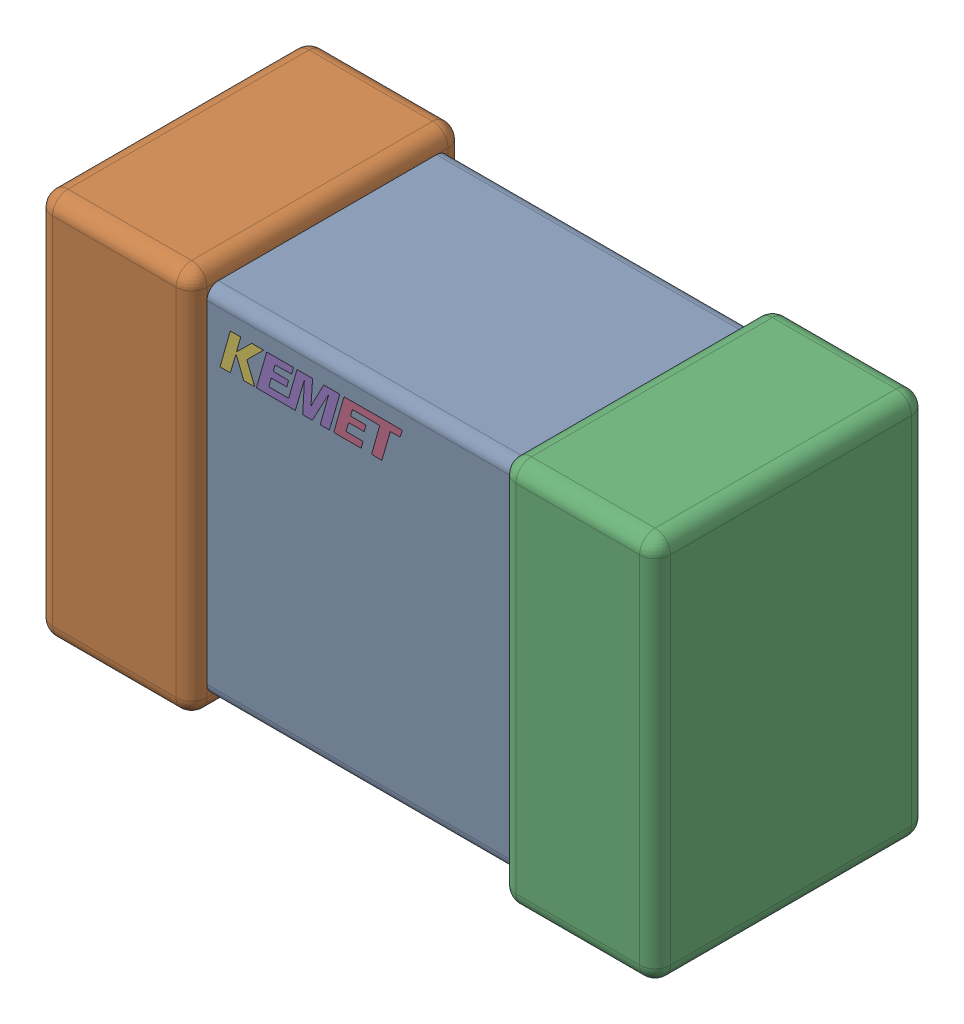
SolidWorks assembly C11.step, configuration Default. Lengths in mm.
Overall size (2 1.25 0.88).
3 component instances, 3 part files, 0 mates.
Components (placement in the parent):
- Cap_KEMET_C0805C472J3HAC_eec.step-1: Cap_KEMET_C0805C472J3HAC_eec.step [Default] at (51.042 28.702 0) size (1 1.15 0.78)
- Cap_KEMET_C0805C472J3HAC_eec-7.step-1: Cap_KEMET_C0805C472J3HAC_eec-7.step [Default] at (51.042 28.702 0) size (2 1.25 0.88)
- Cap_KEMET_C0805C472J3HAC_eec-8.step-1: Cap_KEMET_C0805C472J3HAC_eec-8.step [Default] at (51.042 28.702 0) size (0.59 0.12 0)
